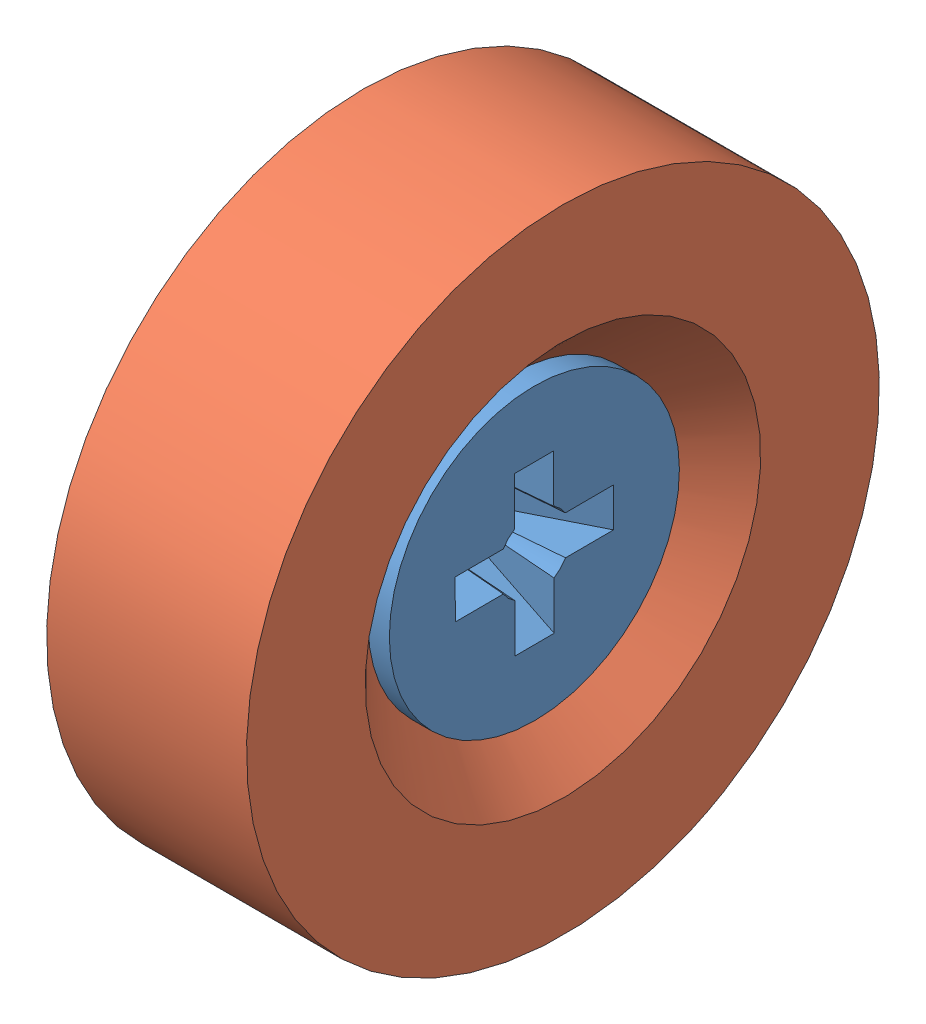
SolidWorks assembly KNURL ADJUSTER, configuration Default. Lengths in mm.
Overall size (19.9 18.13 18.13).
3 component instances, 3 part files, 4 mates.
Components (placement in the parent):
- countersunk flat head cross recess screw_iso-2: countersunk flat head cross recess screw_iso [ISO 7046-1 - M3 x 6 - Z --- 6N] at (21.8182 0 0) x (-1 0 0) z (0 -0.003877 0.999992) size (6 5.5 5.5)
- Adjustable table mount3SLDPRT-1: Adjustable table mount3SLDPRT [Valor predeterminado] at (35.37 36.4165 64.7686) x (0 0.999987 0.005148) z (-1 0 0) size (18.03 18.03 19.9)
- Magnet (12x3.79mm)-1: Magnet (12x3.79mm) [Default] at (22.36 15.0152 -18.2414) x (0 -0.8902 -0.455569) z (-1 0 0) size (12 12 3.79)
Mates (geometry in assembly coordinates):
- Coincident786953: coincident: cone of Magnet (12x3.79mm)-1 through (106.4413 -42.9564 45.6898) axis (0 -1 0); cone of countersunk flat head cross recess screw_iso-2 through (106.4413 -123.8474 45.6898) axis (0 -1 0)
- Paralelo8: parallel anti-aligned: plane of Magnet (12x3.79mm)-1 through (18.57 0 0) normal (-1 0 0); plane of Adjustable table mount3SLDPRT-1 through (18.57 0 0) normal (1 0 0)
- Concentric2: concentric aligned: cylinder of Adjustable table mount3SLDPRT-1 through (18.57 0 0) axis (1 0 0) radius 6; cylinder of Magnet (12x3.79mm)-1 through (18.57 0 0) axis (1 0 0) radius 6
- Coincident786955: coincident anti-aligned: plane of Adjustable table mount3SLDPRT-1 through (18.57 0 0) normal (1 0 0); plane of Magnet (12x3.79mm)-1 through (18.57 0 0) normal (-1 0 0)
